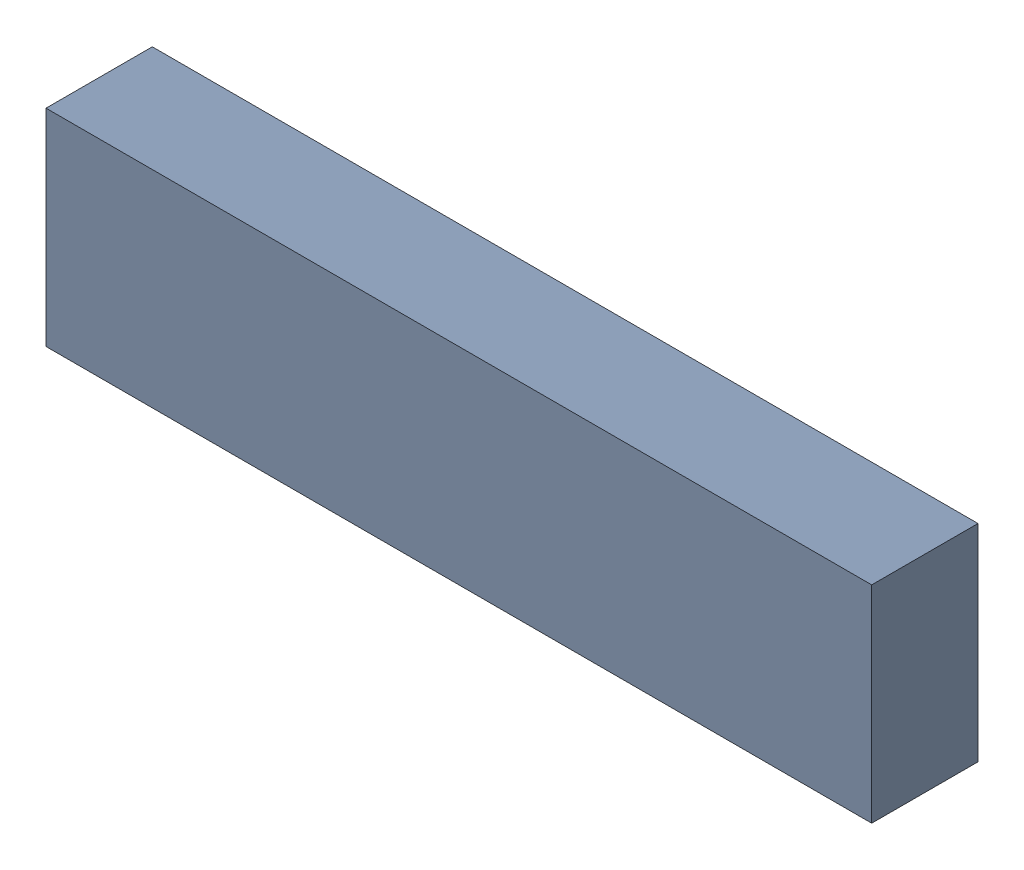
SolidWorks assembly SubmHelice, configuration Default. Lengths in mm.
Overall size (16000 4000 2060).
4 component instances, 4 part files, 7 mates.
Components (placement in the parent):
- Cubo-1: Cubo [Default] at (-8000 2000 -2000) x (1 0 0) z (0 -1 0) size (16000 2060 4000)
- submarino-1: submarino [Default] at (-10572.0107 1812.0539 -1030.3166) x (1 0 0) z (0 1 0) size (4356.11 508.08 730.27)
- Helice-1: Helice [Default] at (-6161.3947 1812.0567 -1030.0965) x (0 0.889445 0.457042) z (0 -0.457042 0.889445) size (327.69 90.3 311.28)
- Cilindro-1: Cilindro [Default] at (-6212.0997 1811.8845 -1030.3777) x (0 -0.924225 -0.381849) z (1 0 0) size (500 500 100)
Mates (geometry in assembly coordinates):
- Coincident1: coincident anti-aligned: plane of Cubo-1 through (-16000 0 -2060) normal (0 -1 0)
- Coincident2: coincident aligned: plane of Cubo-1 through (-8000 2000 0) normal (0 0 1)
- Coincident3: coincident aligned: plane of Cubo-1 through (0 0 -2060) normal (1 0 0)
- Parallel1: parallel aligned: plane of Helice-1 through (-6117.0997 1785.2011 -1044.089) normal (1 0 0)
- Parallel2: parallel aligned: plane of Cilindro-1 through (-6112.0997 1811.8845 -1030.3777) normal (1 0 0)
- Concentric1: concentric aligned: cylinder of Helice-1 through (-6117.0997 1811.8845 -1030.3777) axis (-1 0 0) radius 15; cylinder of Cilindro-1 through (-6112.0997 1811.8845 -1030.3777) axis (-1 0 0) radius 250
- Distance1: distance = 5 mm aligned: plane of Cilindro-1 through (-6112.0997 1811.8845 -1030.3777) normal (1 0 0); plane of Helice-1 through (-6117.0997 1785.2011 -1044.089) normal (1 0 0)
